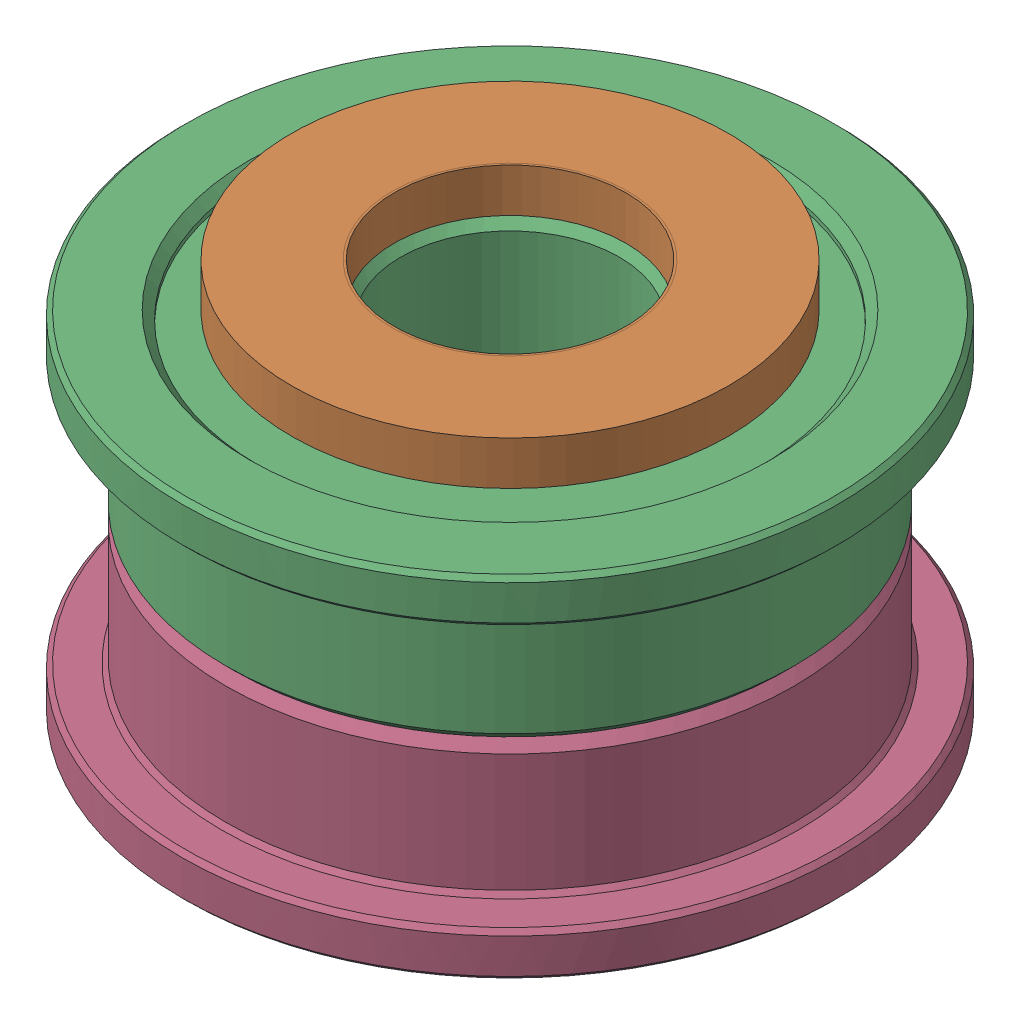
SolidWorks assembly Idler Assembly, configuration Default. Lengths in mm.
Overall size (15 10 15).
4 component instances, 2 part files, 0 mates.
Components (placement in the parent):
- M5 1mm Spacer (1)-1: M5 1mm Spacer (1) [Default] at (0 -1.1 0) x (-0.996195 0 -0.087156) z (0 1 0) size (10 10 1)
- M5 1mm Spacer (1)-2: M5 1mm Spacer (1) [Default] at (0 7.9 0) x (-0.996195 0 -0.087156) z (0 1 0) size (10 10 1)
- F695 ZZ-1: F695 ZZ [Default] at (0 8 0) x (-1 0 0) z (0 0 1) size (15 4 15)
- F695 ZZ-2: F695 ZZ [Default] at origin size (15 4 15)
